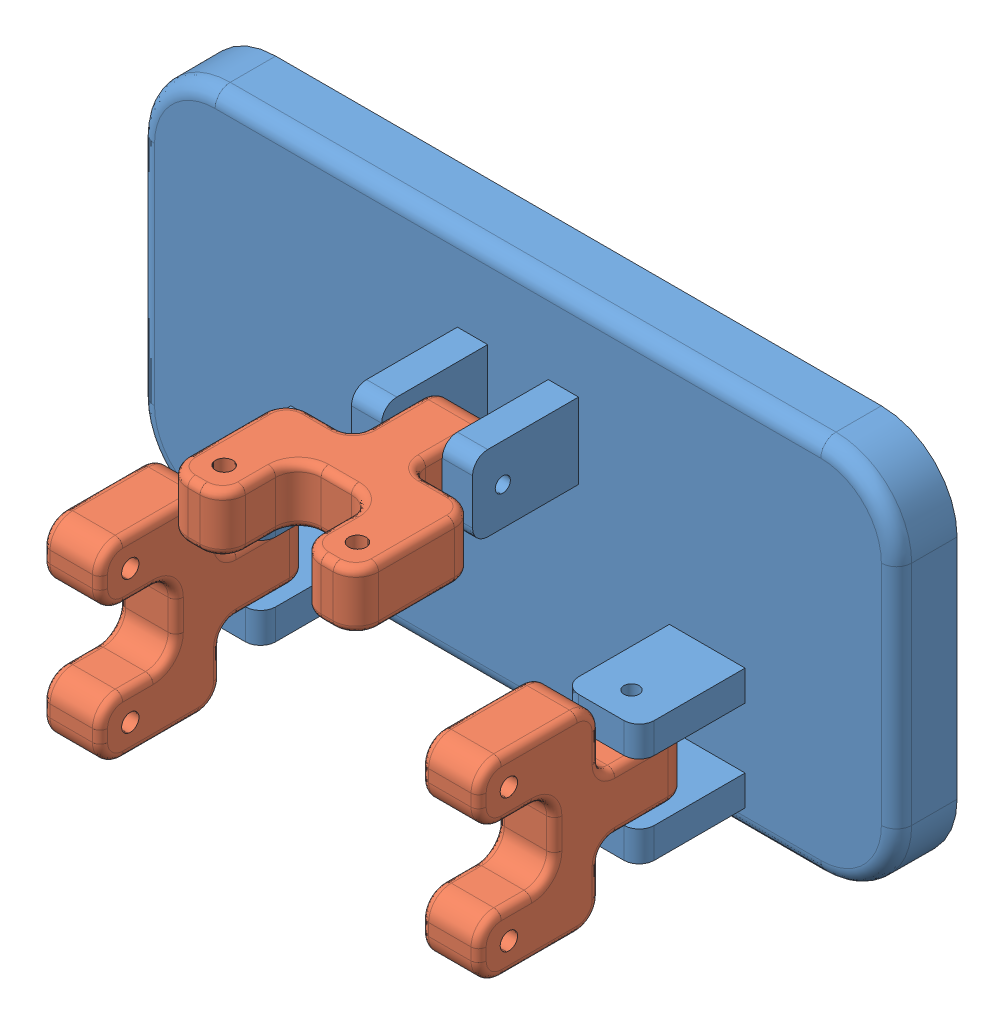
SolidWorks assembly feeta, configuration Default. Lengths in mm.
Overall size (100 51.6 42).
4 component instances, 2 part files, 12 mates.
Components (placement in the parent):
- feet-1: feet [Default] at (0 43.52 -248.23) x (-1 0 0) z (0 1 0) size (100 22 50)
- link2-1: link2 [Default] at (25 29.52 -228.23) x (0 -1 0) z (-1 0 0) size (25.2 28 7.6)
- link2-2: link2 [Default] at (0 52.52 -228.23) x (1 0 0) z (0 -1 0) size (25.2 28 7.6)
- link2-3: link2 [Default] at (-25 29.52 -228.23) x (0 -1 0) z (-1 0 0) size (25.2 28 7.6)
Mates (geometry in assembly coordinates):
- Distance5: distance = 50 mm aligned: plane of feet-1 through (50 28.52 -240.23) normal (1 0 0)
- Distance6: distance = 248.23 mm anti-aligned: plane of feet-1 through (-40 58.52 -248.23) normal (0 0 -1)
- Distance7: distance = 68.52 mm aligned: plane of feet-1 through (40 68.52 -240.23) normal (0 1 0)
- Concentric1: concentric anti-aligned: cylinder of feet-1 through (25 21.52 -230.23) axis (0 1 0) radius 1; cylinder of link2-1 through (25 33.32 -230.23) axis (0 -1 0) radius 1.15
- Distance8: distance = 0.2 mm anti-aligned: plane of link2-1 through (28.8 33.32 -228.23) normal (0 1 0); plane of feet-1 through (30 33.52 -226.23) normal (0 -1 0)
- Parallel1: parallel aligned: plane of feet-1 through (20 33.52 -226.23) normal (-1 0 0); plane of link2-1 through (21.2 29.52 -228.23) normal (-1 0 0)
- Concentric2: concentric aligned: cylinder of feet-1 through (-8 52.52 -230.23) axis (1 0 0) radius 1; cylinder of link2-2 through (-3.8 52.52 -230.23) axis (1 0 0) radius 1.15
- Distance9: distance = 0.2 mm anti-aligned: plane of link2-2 through (-3.8 56.32 -228.23) normal (-1 0 0); plane of feet-1 through (-4 47.52 -226.23) normal (1 0 0)
- Parallel2: parallel aligned: plane of feet-1 through (8 47.52 -226.23) normal (0 -1 0); plane of link2-2 through (0 48.72 -228.23) normal (0 -1 0)
- Concentric3: concentric anti-aligned: cylinder of feet-1 through (-25 21.52 -230.23) axis (0 1 0) radius 1; cylinder of link2-3 through (-25 33.32 -230.23) axis (0 -1 0) radius 1.15
- Distance10: distance = 0.2 mm anti-aligned: plane of link2-3 through (-21.2 33.32 -228.23) normal (0 1 0); plane of feet-1 through (-30 33.52 -226.23) normal (0 -1 0)
- Parallel3: parallel aligned: plane of feet-1 through (-30 33.52 -226.23) normal (-1 0 0); plane of link2-3 through (-28.8 29.52 -228.23) normal (-1 0 0)
